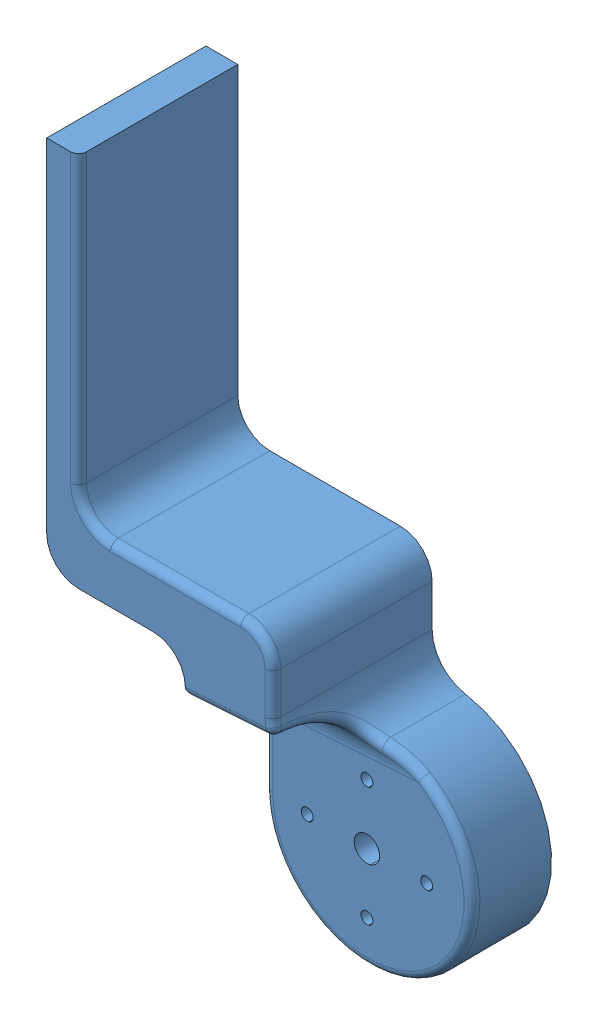
SolidWorks assembly pince + accessoire, configuration Défaut. Lengths in mm.
Overall size (43.4 80 24.59).
2 component instances, 2 part files, 2 mates.
Components (placement in the parent):
- g-1: g [Default] at (13.4937 -20.5034 62.2055) size (43.4 80 20.09)
- dfbvfd-1: dfbvfd [Défaut] at (13.3029 -20.6863 57.7055) x (1 0 0) z (0 -1 0) size (20 5 20)
Mates (geometry in assembly coordinates):
- Coïncidente1: coincident: plane of g-1 through (7.4937 2.4966 62.2055) normal (0 0 -1); plane of dfbvfd-1 through (17.0529 -20.6863 62.2055) normal (0 0 1)
- Coaxiale1: concentric: cylinder of g-1 through (13.3029 -20.6863 63.7055) axis (0 0 -1) radius 10.1; cylinder of dfbvfd-1 through (13.3029 -20.6863 57.7055) axis (0 0 -1) radius 10
